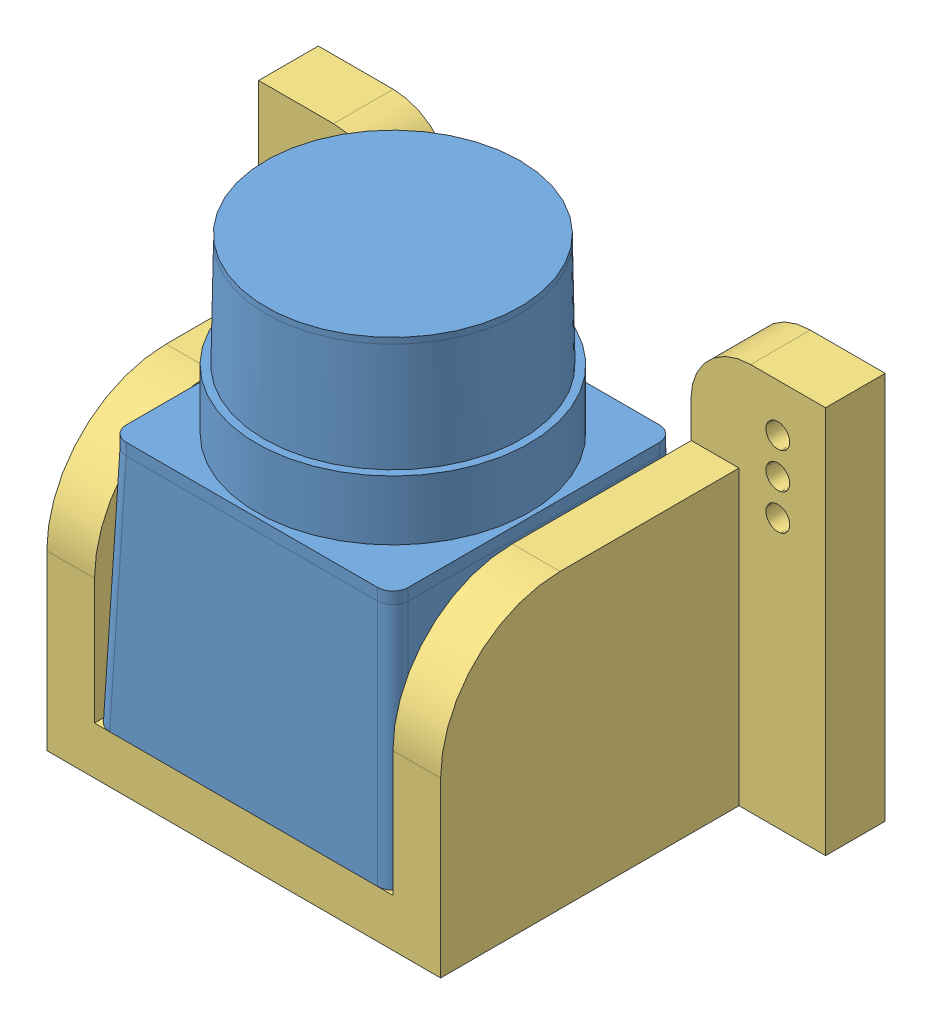
SolidWorks assembly mount-with-R325-URG-04LX-UG01, configuration Default. Lengths in mm.
Overall size (128.21 80.14 60).
3 component instances, 3 part files, 3 mates.
Components (placement in the parent):
- R325-URG-04LX-UG01-1: R325-URG-04LX-UG01 [Default] at (6.5502 -21.3818 11.07) size (50 71 50)
- USB-minib-1: USB-minib [Default] at (-13.8914 -16.7585 25.57) x (0 0 1) z (-0.999391 0.034899 0) size (7.62 4.06 8.79)
- base_laser_mount-1-1: base_laser_mount-1 [Default] at (6.5502 14.6958 -23.93) size (128.21 66.14 60)
Mates (geometry in assembly coordinates):
- Concentric1: concentric: circle of R325-URG-04LX-UG01-1; circle of base_laser_mount-1-1
- Concentric2: concentric: circle of R325-URG-04LX-UG01-1; circle of base_laser_mount-1-1
- Coincident1: coincident anti-aligned: plane of R325-URG-04LX-UG01-1 through (-18.4498 -21.3818 -13.93) normal (0 -1 0); plane of base_laser_mount-1-1 through (6.5502 -21.3818 36.07) normal (0 1 0)
